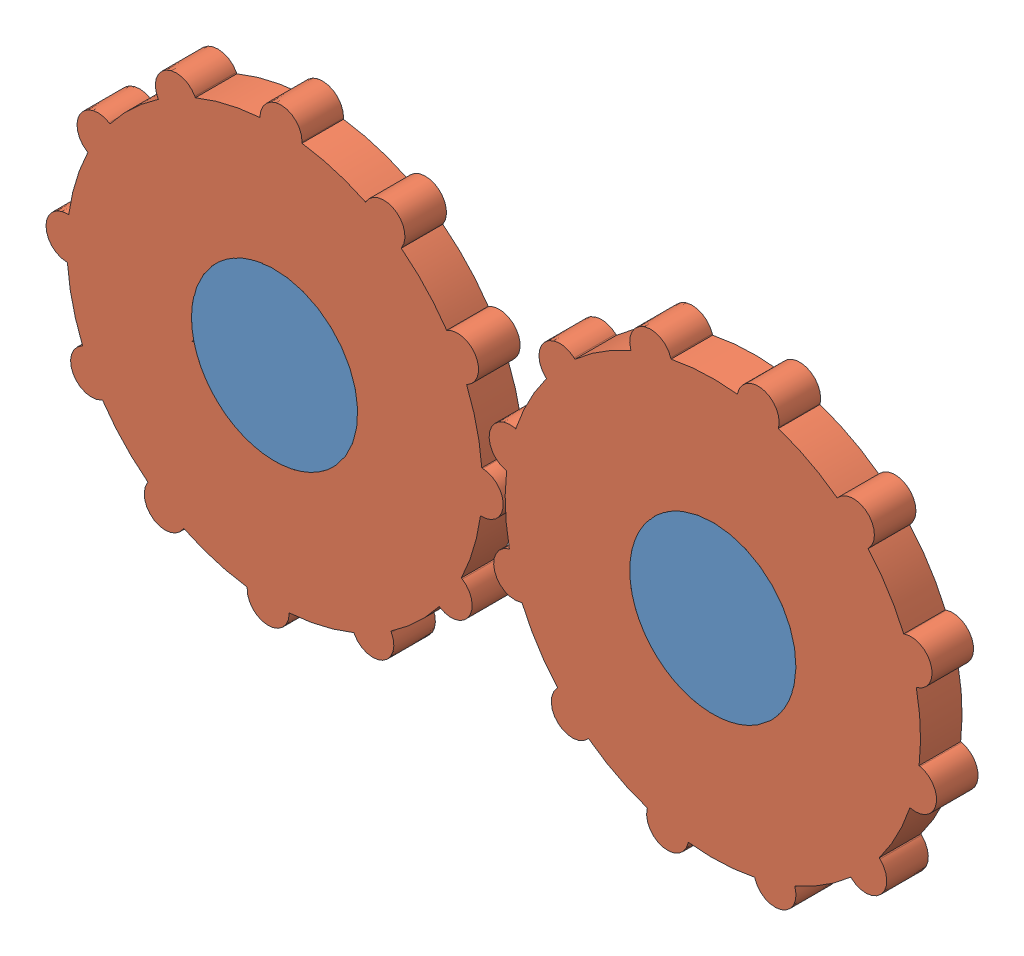
SolidWorks assembly Assem3_anim, configuration Default. Lengths in mm.
Overall size (231.23 138.01 10).
3 component instances, 2 part files, 4 mates.
Components (placement in the parent):
- plane_3d_3-1: plane_3d_3 [Default] at (41.2696 82.5704 114.0541) size (145.5 40 10)
- gear_3d-1: gear_3d [Default] at (-10.0994 77.5395 114.0541) x (0.999524 -0.030837 0) z (0 0 1) size (110.11 110.11 10)
- gear_3d-2: gear_3d [Default] at (95.4006 77.5395 114.0541) x (0.954181 0.299231 0) z (0 0 1) size (110.11 110.11 10)
Mates (geometry in assembly coordinates):
- Coincident1: coincident aligned: plane of plane_3d_3-1 through (41.2696 82.5704 124.0541) normal (0 0 1); plane of gear_3d-1 through (-10.0994 77.5395 124.0541) normal (0 0 1)
- Coincident2: coincident aligned: plane of plane_3d_3-1 through (41.2696 82.5704 124.0541) normal (0 0 1); plane of gear_3d-2 through (95.4006 77.5395 124.0541) normal (0 0 1)
- Coincident3: coincident aligned: circle of plane_3d_3-1; circle of gear_3d-1
- Coincident4: coincident aligned: circle of plane_3d_3-1; circle of gear_3d-2
